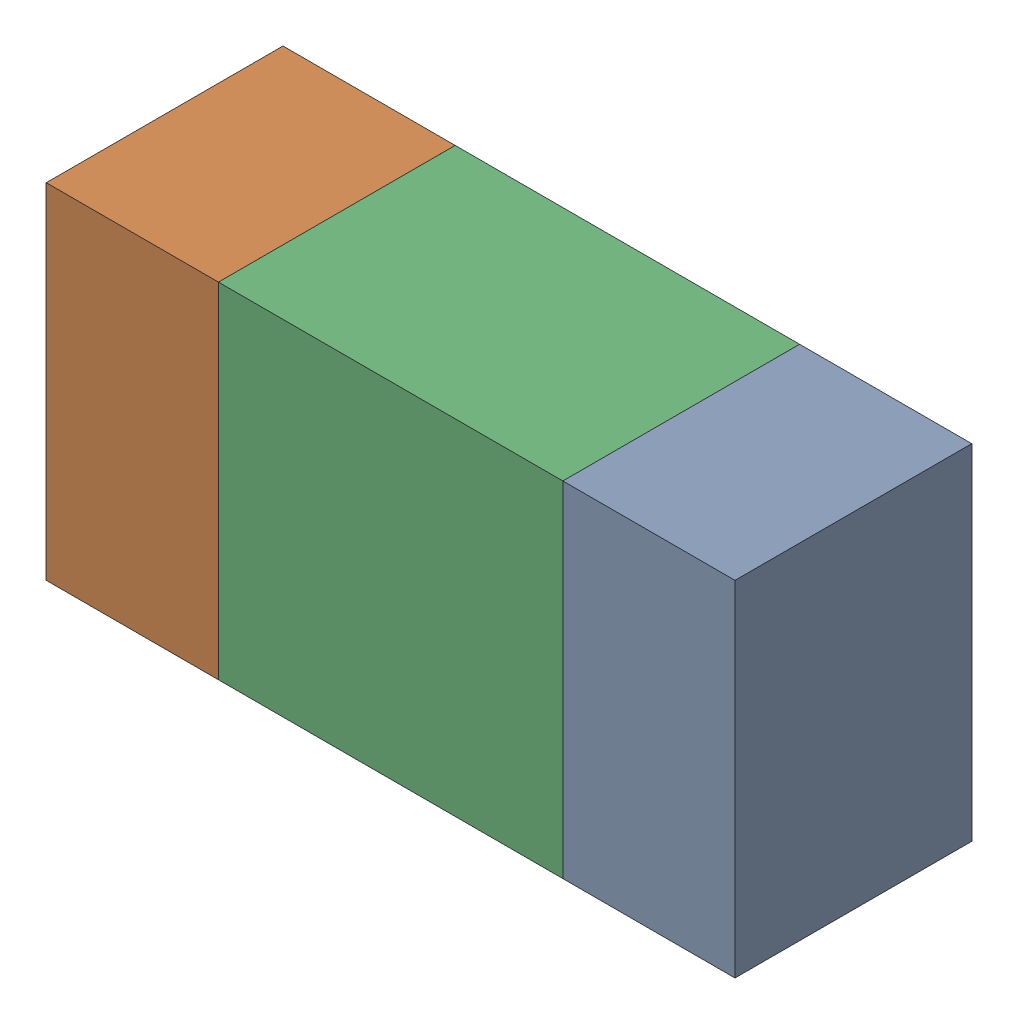
SolidWorks assembly R24, configuration ﾃﾞﾌｫﾙﾄ. Lengths in mm.
Overall size (1.6 0.8 0.55).
6 component instances, 2 part files, 0 mates.
Components (placement in the parent):
- 689261512-1: 689261512 [ﾃﾞﾌｫﾙﾄ] at (11.3949 19.3676 -1.7503) size (0.4 0.8 0.55)
  - Extruded_32-1: Extruded_32 [ﾃﾞﾌｫﾙﾄ] at origin size (0.4 0.8 0.55)
- 689261512-2: 689261512 [ﾃﾞﾌｫﾙﾄ] at (10.1949 19.3676 -1.7503) size (0.4 0.8 0.55)
  - Extruded_32-1: Extruded_32 [ﾃﾞﾌｫﾙﾄ] at origin size (0.4 0.8 0.55)
- 689261648-1: 689261648 [ﾃﾞﾌｫﾙﾄ] at (10.795 19.3676 -1.7503) size (0.8 0.8 0.55)
  - Extruded_33-1: Extruded_33 [ﾃﾞﾌｫﾙﾄ] at origin size (0.8 0.8 0.55)
